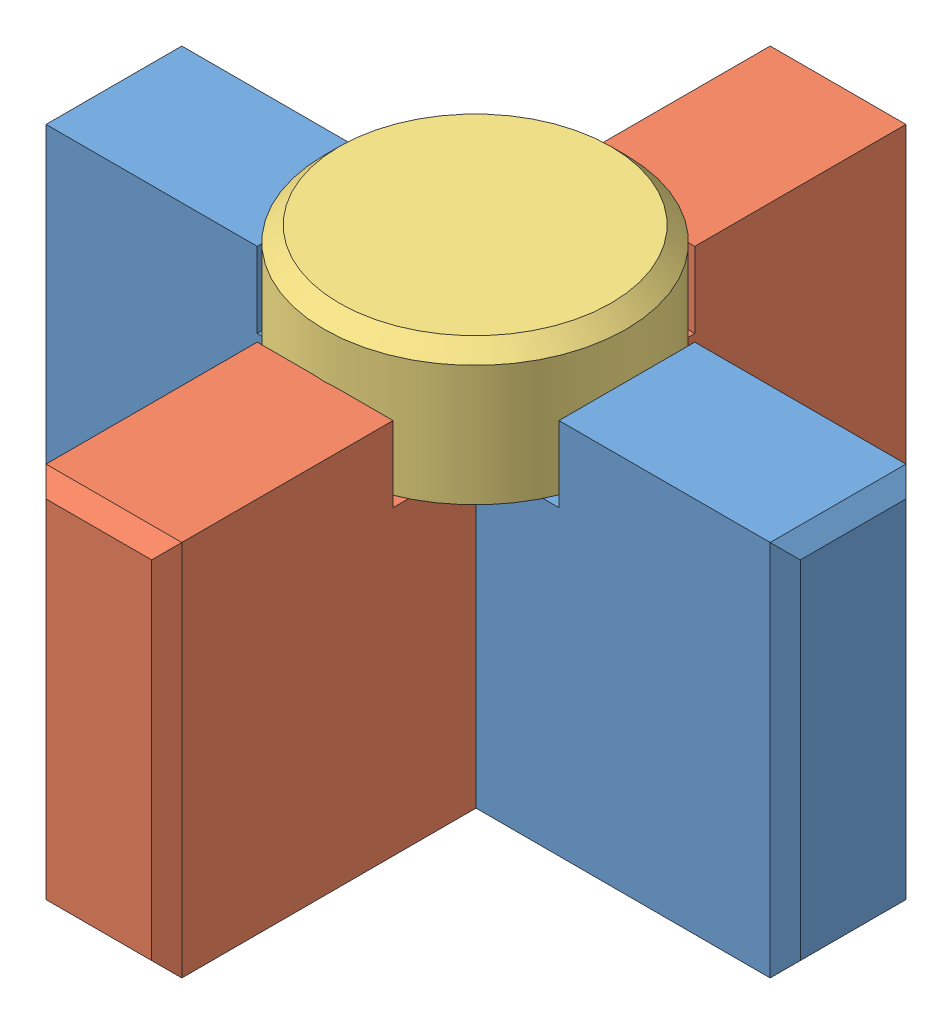
SolidWorks assembly candle stand assembly, configuration Default. Lengths in mm.
Overall size (100 58 100).
3 component instances, 3 part files, 6 mates.
Components (placement in the parent):
- candle stand 1-1: candle stand 1 [Default] at (40.7154 25 0) x (1 0 0) z (0 0 -1) size (100 50 18)
- candle stand 2-1: candle stand 2 [Default] at (31.7154 25 -9) x (0 0 -1) z (1 0 0) size (100 50 18)
- tea light-1: tea light [Default] at (40.6942 40 -8.9085) size (40 18 40)
Mates (geometry in assembly coordinates):
- Coincident4: coincident anti-aligned: plane of candle stand 1-1 through (90.7154 0 -18) normal (0 -1 0); plane of assembly through (0 0 0) normal (0 1 0)
- Coincident7: coincident aligned: plane of candle stand 1-1 through (40.7154 25 0) normal (0 0 1); plane of assembly through (0 0 0) normal (0 0 1)
- Coincident10: coincident anti-aligned: plane of candle stand 1-1 through (40.7154 25 0) normal (0 0 1); plane of candle stand 2-1 through (29.7154 25 0) normal (0 0 -1)
- Coincident11: coincident anti-aligned: plane of candle stand 1-1 through (60.7154 40 2) normal (0 1 0); plane of tea light-1 through (40.6942 40 -8.9085) normal (0 -1 0)
- Coincident12: coincident anti-aligned: plane of candle stand 1-1 through (31.7154 25 0) normal (0 -1 0); plane of candle stand 2-1 through (29.7154 25 -18) normal (0 1 0)
- Coincident13: coincident anti-aligned: plane of candle stand 1-1 through (31.7154 0 0) normal (1 0 0); plane of candle stand 2-1 through (31.7154 25 -9) normal (-1 0 0)
